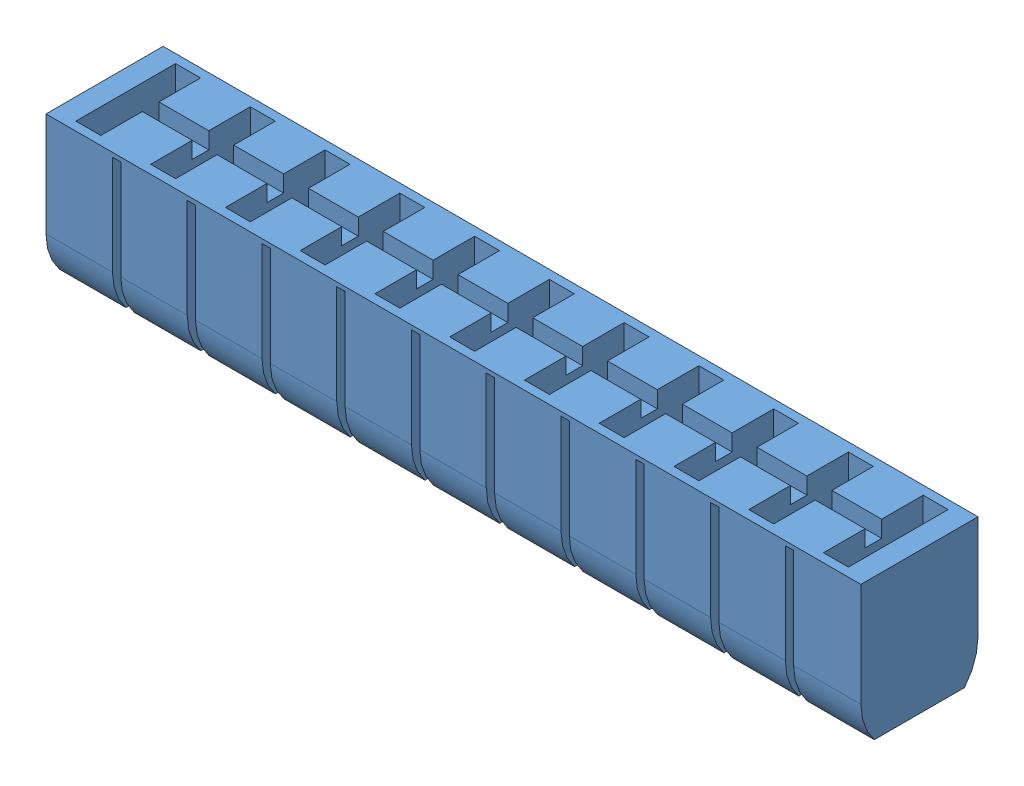
SolidWorks assembly molded_part, configuration Default. Lengths in mm.
Overall size (98.1 22.3 21.26).
3 component instances, 3 part files, 2 mates.
Components (placement in the parent):
- SR_Oct31_female-1: SR_Oct31_female [Default] at (273.3707 24.65 186.4049) size (100 22 46) (hidden)
- blank-1: blank [Default] at (-1.6881 28.15 74.8755) size (98.1 22.3 21.26)
- SR_oct31_Male-1: SR_oct31_Male [Default] at (98.3119 47.1536 90.8755) x (-1 0 0) z (0 0 1) size (100 18 46) (hidden)
Mates (geometry in assembly coordinates):
- Coincident12: coincident: plane of SR_Oct31_female-1 through (-1.6881 44.65 74.8755) normal (-1 0 0); plane of SR_oct31_Male-1 through (-1.6881 44.1536 90.8755) normal (-1 0 0)
- Coincident13: coincident: plane of SR_Oct31_female-1 through (-1.6881 44.65 74.8755) normal (0 0 -1); plane of SR_oct31_Male-1 through (98.3119 41.1536 74.8755) normal (0 0 -1)
